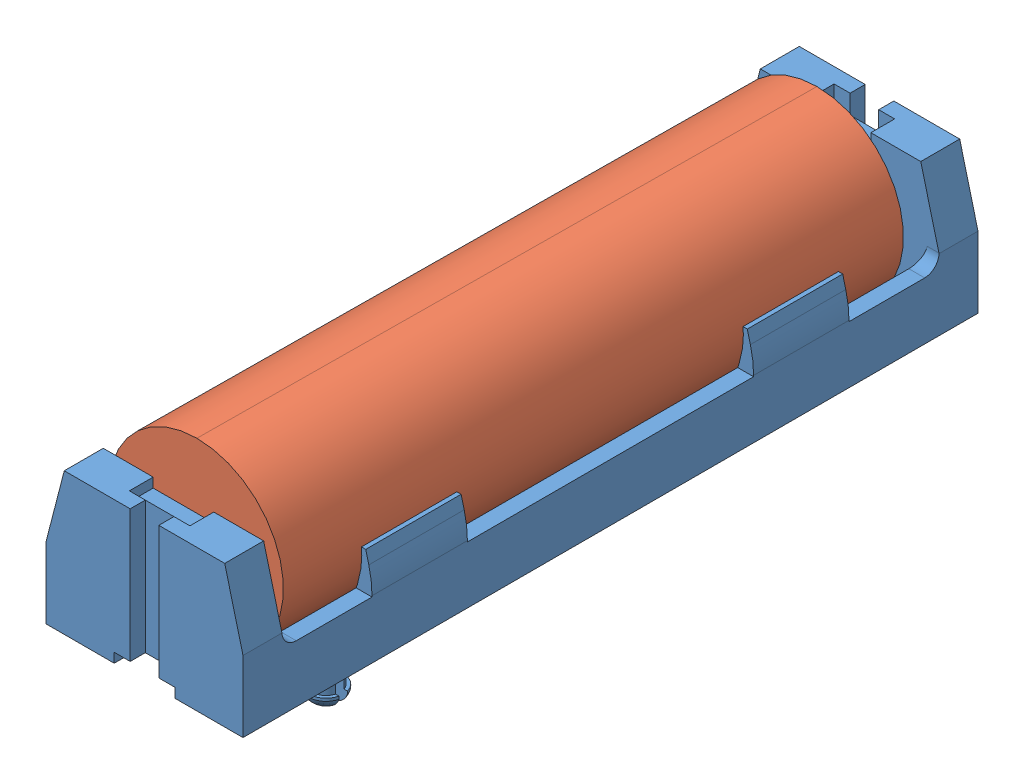
SolidWorks assembly Assem2, configuration Default. Lengths in mm.
Overall size (20.65 22.65 77.05).
2 component instances, 2 part files, 0 mates.
Components (placement in the parent):
- KEYS1042.step-1: KEYS1042.step [Default] at (28.7379 30.3842 61.8985) size (20.65 18.15 77.05)
- 18650Battery.step-1: 18650Battery.step [Default] at (28.8299 40.0282 30.1042) x (1 0 0) z (0 -0.999962 0.008727) size (18.3 65 18.3)
